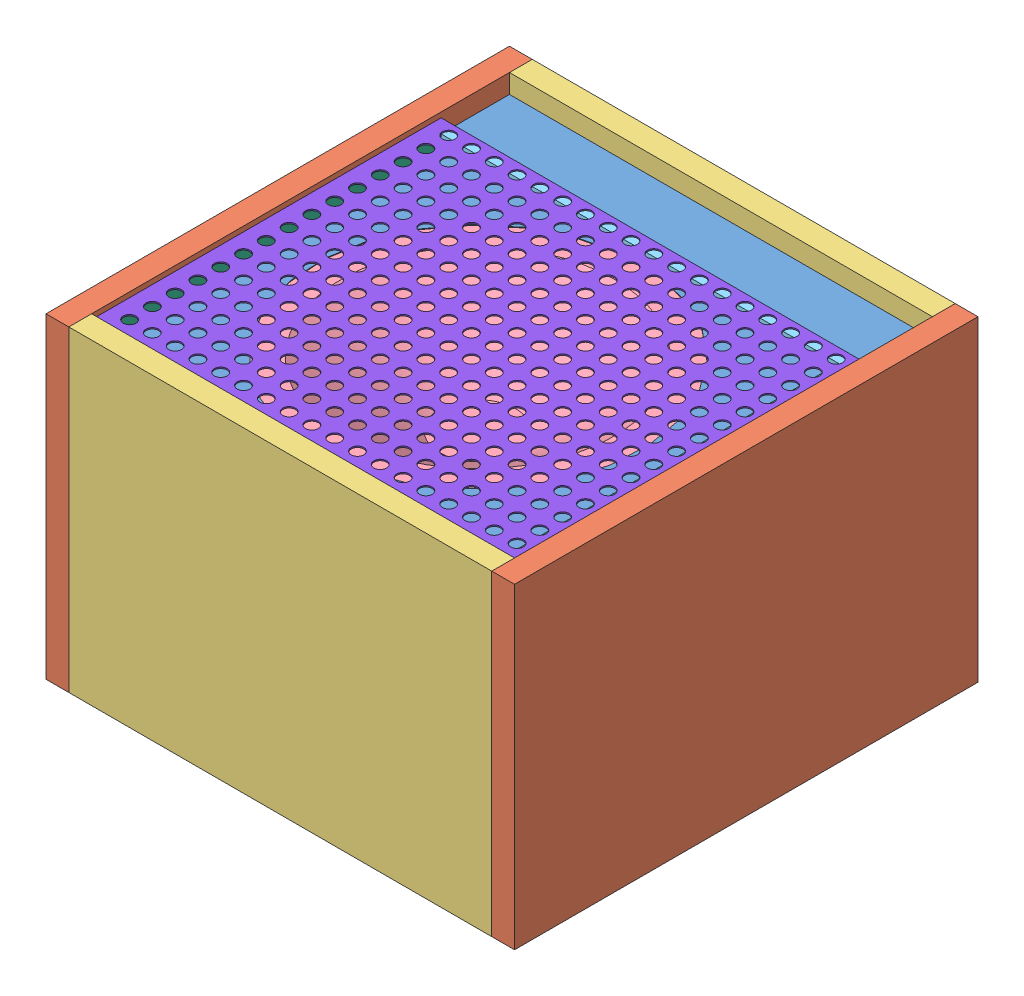
SolidWorks assembly _assmbly, configuration По умолчанию. Lengths in mm.
Overall size (370 250 371.24).
12 component instances, 8 part files, 30 mates.
Components (placement in the parent):
- front-1: front [По умолчанию] at (192.6521 219.7719 236.7568) size (344 18 340)
- mid_h-1: mid_h [По умолчанию] at (7.6521 127.7719 236.7568) x (0 -1 0) z (1 0 0) size (250 366 18)
- mid_l-1: mid_l [По умолчанию] at (192.6521 127.7719 419.7568) x (1 0 0) z (0 1 0) size (334 18 250)
- mid_l-2: mid_l [По умолчанию] at (192.6521 127.7719 53.7568) x (-1 0 0) z (0 1 0) size (334 18 250)
- mid_h-2: mid_h [По умолчанию] at (377.6521 127.7719 236.7568) x (0 -1 0) z (-1 0 0) size (250 366 18)
- speaker-1: speaker [По умолчанию] at (192.6521 237.2719 263.7568) x (-0.951256 0 0.308401) z (0.308401 0 0.951256) size (256 104 256)
- rail_h-1: rail_h [По умолчанию] at (25.6521 242.7719 396.7568) x (0 0 1) z (0 1 0) size (10 334 10)
- rail_h-2: rail_h [По умолчанию] at (25.6521 242.7719 130.7568) x (0 0 -1) z (0 -1 0) size (10 334 10)
- rail_v-1: rail_v [По умолчанию] at (30.6521 242.7719 135.7568) x (0 1 0) z (1 0 0) size (10 256 10)
- rail_v-2: rail_v [По умолчанию] at (354.6521 242.7719 135.7568) x (1 0 0) z (0 -1 0) size (10 256 10)
- tr_mains-1: tr_mains [По умолчанию] at (78.1521 84.8086 401.7568) x (1 0 0) z (0 1 0) size (105 115 125)
- grill-1: grill [По умолчанию] at (192.6521 247.7719 263.7568) size (334 1 276)
Mates (geometry in assembly coordinates):
- Совпадение13: coincident aligned: plane of mid_l-1 through (192.6521 127.7719 419.7568) normal (0 0 1); plane of mid_h-2 through (359.6521 2.7719 419.7568) normal (0 0 1)
- Совпадение14: coincident anti-aligned: plane of mid_l-1 through (359.6521 252.7719 401.7568) normal (1 0 0); plane of mid_h-2 through (359.6521 127.7719 236.7568) normal (-1 0 0)
- Совпадение15: coincident aligned: plane of mid_l-1 through (359.6521 2.7719 401.7568) normal (0 -1 0); plane of mid_h-2 through (359.6521 2.7719 53.7568) normal (0 -1 0)
- Совпадение16: coincident aligned: plane of mid_l-2 through (25.6521 2.7719 71.7568) normal (0 -1 0); plane of mid_h-2 through (359.6521 2.7719 53.7568) normal (0 -1 0)
- Совпадение17: coincident anti-aligned: plane of mid_l-2 through (359.6521 252.7719 71.7568) normal (1 0 0); plane of mid_h-2 through (359.6521 127.7719 236.7568) normal (-1 0 0)
- Совпадение18: coincident aligned: plane of mid_l-2 through (192.6521 127.7719 53.7568) normal (0 0 -1); plane of mid_h-2 through (359.6521 2.7719 53.7568) normal (0 0 -1)
- Совпадение19: coincident aligned: plane of mid_h-1 through (25.6521 2.7719 53.7568) normal (0 0 -1); plane of mid_l-2 through (192.6521 127.7719 53.7568) normal (0 0 -1)
- Совпадение20: coincident anti-aligned: plane of mid_h-1 through (25.6521 127.7719 236.7568) normal (1 0 0); plane of mid_l-2 through (25.6521 252.7719 71.7568) normal (-1 0 0)
- Совпадение21: coincident aligned: plane of mid_h-1 through (25.6521 2.7719 419.7568) normal (0 -1 0); plane of mid_l-2 through (25.6521 2.7719 71.7568) normal (0 -1 0)
- Совпадение22: coincident aligned: line of front-1 through (364.6521 237.7719 66.7568) axis (-1 0 0); line of mid_l-2 through (359.6521 237.7719 66.7568) axis (-1 0 0)
- Совпадение23: coincident aligned: line of front-1 through (364.6521 237.7719 406.7568) axis (0 0 -1); line of mid_h-2 through (364.6521 237.7719 406.7568) axis (0 0 -1)
- Совпадение24: coincident anti-aligned: plane of front-1 through (192.6521 229.7719 263.7568) normal (0 1 0); plane of speaker-1 through (192.6521 229.7719 263.7568) normal (0 -1 0)
- Концентричный1: concentric anti-aligned: circle of front-1; circle of speaker-1
- Совпадение25: coincident anti-aligned: line of mid_l-1 through (25.6521 237.7719 401.7568) axis (1 0 0); line of rail_h-1 through (359.6521 237.7719 401.7568) axis (-1 0 0)
- Совпадение26: coincident: plane of mid_l-1 through (192.6521 127.7719 401.7568) normal (0 0 -1); line of rail_h-1 through (359.6521 247.7719 401.7568) axis (-1 0 0)
- Совпадение27: coincident anti-aligned: plane of mid_h-2 through (359.6521 127.7719 236.7568) normal (-1 0 0); plane of rail_h-1 through (359.6521 242.7719 396.7568) normal (1 0 0)
- Совпадение28: coincident anti-aligned: plane of front-1 through (192.6521 237.7719 236.7568) normal (0 1 0); plane of rail_h-2 through (359.6521 237.7719 125.7568) normal (0 -1 0)
- Совпадение30: coincident anti-aligned: plane of mid_h-2 through (359.6521 127.7719 236.7568) normal (-1 0 0); plane of rail_h-2 through (359.6521 242.7719 130.7568) normal (1 0 0)
- Расстояние1: distance = 54 mm anti-aligned: plane of rail_h-2 through (359.6521 247.7719 125.7568) normal (0 0 -1); plane of mid_l-2 through (192.6521 127.7719 71.7568) normal (0 0 1)
- Совпадение32: coincident aligned: plane of rail_h-1 through (359.6521 247.7719 401.7568) normal (0 1 0); plane of rail_v-2 through (359.6521 247.7719 391.7568) normal (0 1 0)
- Совпадение33: coincident anti-aligned: plane of mid_h-2 through (359.6521 127.7719 236.7568) normal (-1 0 0); plane of rail_v-2 through (359.6521 237.7719 391.7568) normal (1 0 0)
- Совпадение34: coincident anti-aligned: plane of rail_h-1 through (359.6521 237.7719 391.7568) normal (0 0 -1); plane of rail_v-2 through (354.6521 242.7719 391.7568) normal (0 0 1)
- Совпадение35: coincident aligned: plane of rail_h-1 through (359.6521 247.7719 401.7568) normal (0 1 0); plane of rail_v-1 through (35.6521 247.7719 391.7568) normal (0 1 0)
- Совпадение36: coincident anti-aligned: plane of mid_h-1 through (25.6521 127.7719 236.7568) normal (1 0 0); plane of rail_v-1 through (25.6521 247.7719 391.7568) normal (-1 0 0)
- Совпадение37: coincident anti-aligned: plane of rail_h-1 through (359.6521 237.7719 391.7568) normal (0 0 -1); plane of rail_v-1 through (30.6521 242.7719 391.7568) normal (0 0 1)
- Совпадение38: coincident anti-aligned: plane of mid_l-1 through (192.6521 127.7719 401.7568) normal (0 0 -1); plane of tr_mains-1 through (78.1521 84.8086 401.7568) normal (0 0 1)
- Совпадение39: coincident anti-aligned: plane of mid_h-1 through (25.6521 127.7719 236.7568) normal (1 0 0); plane of tr_mains-1 through (25.6521 147.3086 286.7568) normal (-1 0 0)
- Совпадение40: coincident anti-aligned: plane of rail_h-2 through (359.6521 247.7719 125.7568) normal (0 1 0); plane of grill-1 through (192.6521 247.7719 263.7568) normal (0 -1 0)
- Совпадение41: coincident aligned: plane of rail_h-2 through (359.6521 247.7719 125.7568) normal (0 0 -1); plane of grill-1 through (359.6521 248.7719 125.7568) normal (0 0 -1)
- Совпадение42: coincident anti-aligned: plane of mid_h-1 through (25.6521 127.7719 236.7568) normal (1 0 0); plane of grill-1 through (25.6521 248.7719 401.7568) normal (-1 0 0)
